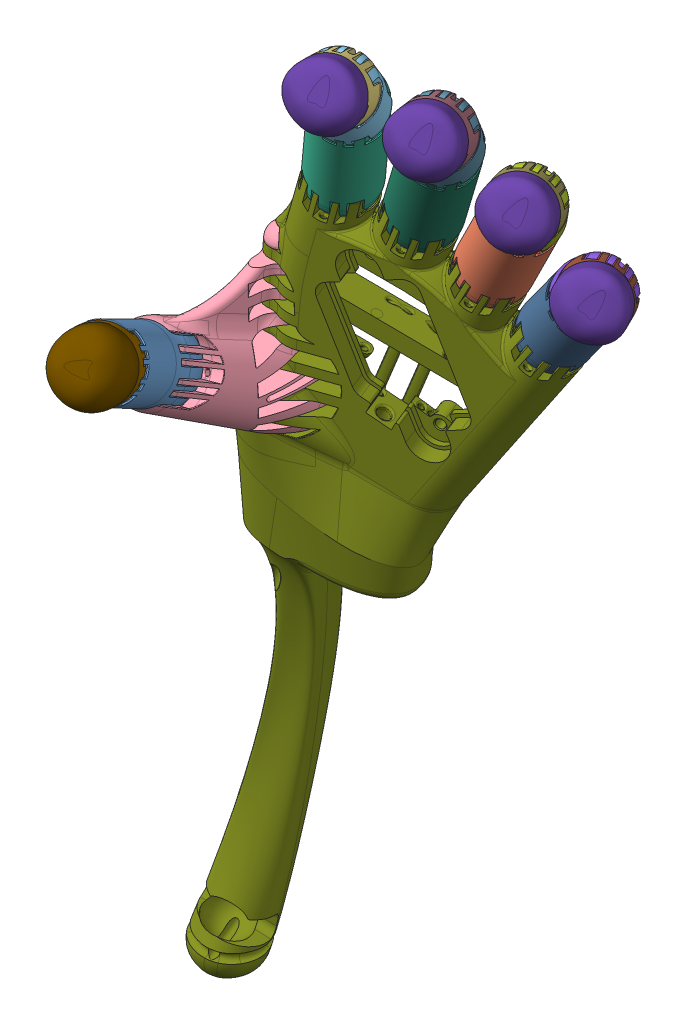
SolidWorks assembly hand_links_0, configuration linksStandard. Lengths in mm.
Overall size (174.74 277.21 120.1).
21 component instances, 18 part files, 45 mates.
Components (placement in the parent):
- p-daumen-seg-2-step-v01-2: p-daumen-seg-2-step-v01 [linksStandard] at (-105.8085 -71.1368 89.6014) x (-0.231233 0.848379 -0.476218) z (0.953119 0.09934 -0.285823) size (20.69 43.22 21.88)
- p-ringfinger-seg-1-step-v02-2: p-ringfinger-seg-1-step-v02 [linksStandard] at (-82.2721 -87.3923 31.2992) x (0.834897 -0.441986 -0.328018) z (0.167049 -0.364366 0.916151) size (19.08 47.31 19.03)
- p-zeigfinger-seg-3-step-v02-2: p-zeigfinger-seg-3-step-v02 [linksStandard] at (-122.5785 -47.8794 -30.4367) x (0.907236 -0.246273 -0.340988) z (-0.050565 -0.868652 0.492835) size (19.01 23.27 19)
- p-daumen-seg-1-step-v01-2: p-daumen-seg-1-step-v01 [linksStandard] at (-100.474 -88.1528 56.8024) x (-0.144961 -0.741973 0.654571) z (-0.983441 0.035324 -0.177752) size (51 61.46 25.3)
- p-zeigfinger-seg-2-step-v02-2: p-zeigfinger-seg-2-step-v02 [linksStandard] at (-137.8276 -111.3733 -25.0048) x (0.907236 -0.246273 -0.340988) z (0.095303 -0.66924 0.736909) size (19.2 35.59 19.73)
- p-zeigfinger-seg-1-step-v02-2: p-zeigfinger-seg-1-step-v02 [linksStandard] at (-104.3344 -77.6629 39.9073) x (0.907236 -0.246273 -0.340988) z (0.229675 -0.389107 0.892101) size (19.08 48.86 19.03)
- p-ringfinger-seg-2-step-v02-2: p-ringfinger-seg-2-step-v02 [linksStandard] at (-123.5586 -119.2331 -31.035) x (0.834897 -0.441986 -0.328018) z (-0.022395 -0.622741 0.782107) size (19.2 37.93 19.73)
- p-kleinerfinger-seg-2-step-v02-2: p-kleinerfinger-seg-2-step-v02 [linksStandard] at (-101.3561 -110.3796 -16.5005) x (0.780209 -0.540448 -0.314944) z (-0.081347 -0.586882 0.805575) size (19.09 34.83 19.68)
- p-daumen-seg-3-v01-2: p-daumen-seg-3-v01 [linksStandard] at (-101.2428 -59.0462 109.0287) x (0.509394 0.522602 0.68367) z (0.828884 -0.084496 -0.553002) size (28.23 20.09 20.4)
- p-kleinerfinger-seg-1-step-v02-2: p-kleinerfinger-seg-1-step-v02 [linksStandard] at (-75.3128 -98.5287 27.5212) x (0.780209 -0.540448 -0.314944) z (0.135682 -0.345286 0.928638) size (19.08 41.2 19.03)
- p-kleinerfinger-seg-3-step-v02-2: p-kleinerfinger-seg-3-step-v02 [linksStandard] at (-96.9388 -81.2121 -55.4508) x (0.780209 -0.540448 -0.314944) z (-0.288564 -0.757692 0.585349) size (18.67 21.72 17.82)
- p-ringfinger-seg-3-step-v02-2: p-ringfinger-seg-3-step-v02 [linksStandard] at (-96.3832 -59.946 -41.5997) x (0.834897 -0.441986 -0.328018) z (-0.209139 -0.806005 0.55373) size (19.01 23.27 19)
- p-mittelfinger-seg-3-step-v02-2: p-mittelfinger-seg-3-step-v02 [linksStandard] at (-88.7612 -32.6771 -4.2991) x (0.875864 -0.346025 -0.336346) z (-0.131494 -0.84177 0.523577) size (19.01 24.05 19)
- p-mittelfinger-seg-2-step-v02-2: p-mittelfinger-seg-2-step-v02 [linksStandard] at (-85.001 -49.817 23.2747) x (0.875864 -0.346025 -0.336346) z (0.035235 -0.649287 0.759727) size (19.2 39.53 19.78)
- p-mittelfinger-seg-1-step-v02-2: p-mittelfinger-seg-1-step-v02 [linksStandard] at (-109.2309 -113.1606 25.1963) x (0.875864 -0.346025 -0.336346) z (0.197714 -0.378491 0.904242) size (19.08 48.86 19.03)
- p-handfläche-teil-2-v01-2: p-handfläche-teil-2-v01 [linksStandard] at (-93.4775 -100.6279 53.4744) x (-0.875864 0.346025 0.336346) z (-0.336346 0.062043 -0.939693) size (71.41 221.99 39.87)
- p-fingerkuppe-12.4-1: p-fingerkuppe-12.4 [linksStandard] at (-9.4631 -23.5529 62.3085) x (0.780209 -0.540448 -0.314944) z (-0.288564 -0.757692 0.585349) size (17.55 9.03 17.93)
- p-fingerkuppe-12.4-5: p-fingerkuppe-12.4 [linksStandard] at (-19.9026 -0.8036 73.3735) x (0.834897 -0.441986 -0.328018) z (-0.209139 -0.806005 0.55373) size (17.55 9.03 17.93)
- p-fingerkuppe-12.4-6: p-fingerkuppe-12.4 [linksStandard] at (-37.0914 13.4349 82.8131) x (0.875864 -0.346025 -0.336346) z (-0.131494 -0.84177 0.523577) size (17.55 9.03 17.93)
- p-fingerkuppe-12.4-7: p-fingerkuppe-12.4 [linksStandard] at (-60.7662 15.7541 88.0632) x (0.907236 -0.246273 -0.340988) z (-0.050565 -0.868652 0.492835) size (17.55 9.03 17.93)
- p-fingerkuppe-18-1: p-fingerkuppe-18 [Standard] at (-90.1493 -47.6651 123.9175) x (0.231233 -0.848379 0.476218) z (-0.828884 0.084496 0.553002) size (18.01 12.53 19.06)
Mates (geometry in assembly coordinates):
- Concentric1: concentric aligned: cylinder of p-daumen-seg-1-step-v01-2 through (-99.5527 -52.2226 58.8448) axis (-0.025594 -0.998061 -0.056736) radius 1; cylinder of p-handfläche-teil-2-v01-2 through (-99.5527 -52.2226 58.8448) axis (-0.025594 -0.998061 -0.056736) radius 1.3
- Coincident1: coincident anti-aligned: plane of p-daumen-seg-1-step-v01-2 through (-99.5527 -52.2226 58.8448) normal (-0.025594 -0.998061 -0.056736); plane of p-handfläche-teil-2-v01-2 through (-88.5057 -53.1849 70.7899) normal (0.025594 0.998061 0.056736)
- Concentric2: concentric anti-aligned: cylinder of p-daumen-seg-2-step-v01-2 through (-107.6815 -64.2649 85.7441) axis (0.231233 -0.848379 0.476218) radius 3.3; cylinder of p-daumen-seg-1-step-v01-2 through (-107.7393 -64.0528 85.625) axis (-0.231233 0.848379 -0.476218) radius 3.6
- Distance1: distance = 0.25 mm anti-aligned: plane of p-daumen-seg-2-step-v01-2 through (-119.5206 -72.725 78.311) normal (-0.231233 0.848379 -0.476218); plane of p-daumen-seg-1-step-v01-2 through (-96.3972 -65.2495 79.8758) normal (0.231233 -0.848379 0.476218)
- Concentric3: concentric aligned: cylinder of p-daumen-seg-2-step-v01-2 through (-102.9886 -52.641 105.4333) axis (0.231233 -0.848379 0.476218) radius 3; cylinder of p-daumen-seg-3-v01-2 through (-102.9076 -52.9379 105.5999) axis (0.231233 -0.848379 0.476218) radius 3.3
- Distance2: distance = 0.25 mm anti-aligned: plane of p-daumen-seg-3-v01-2 through (-103.6879 -54.4436 120.9353) normal (0.231233 -0.848379 0.476218); plane of p-daumen-seg-2-step-v01-2 through (-112.2538 -66.1057 104.8438) normal (-0.231233 0.848379 -0.476218)
- Concentric4: concentric aligned: cylinder of p-zeigfinger-seg-1-step-v02-2 through (-78.2575 -33.4931 52.4593) axis (-0.907236 0.246273 0.340988) radius 3.05; cylinder of p-handfläche-teil-2-v01-2 through (-91.8207 -29.8113 57.557) axis (-0.907236 0.246273 0.340988) radius 3.35
- Concentric5: concentric aligned: cylinder of p-zeigfinger-seg-2-step-v02-2 through (-67.2492 -5.8892 61.6651) axis (-0.907236 0.246273 0.340988) radius 3.05; cylinder of p-zeigfinger-seg-1-step-v02-2 through (-69.109 -5.3843 62.3641) axis (-0.907236 0.246273 0.340988) radius 3.35
- Concentric6: concentric aligned: cylinder of p-zeigfinger-seg-3-step-v02-2 through (-59.875 6.6394 72.0896) axis (-0.907236 0.246273 0.340988) radius 3.05; cylinder of p-zeigfinger-seg-2-step-v02-2 through (-61.7349 7.1443 72.7886) axis (-0.907236 0.246273 0.340988) radius 3.35
- Distance3: distance = 0.25 mm anti-aligned: plane of p-zeigfinger-seg-3-step-v02-2 through (-69.5267 12.1422 63.5511) normal (0.907236 -0.246273 -0.340988); plane of p-zeigfinger-seg-2-step-v02-2 through (-63.5081 19.9985 73.157) normal (-0.907236 0.246273 0.340988)
- Distance4: distance = 0.25 mm anti-aligned: plane of p-zeigfinger-seg-1-step-v02-2 through (-72.5115 6.6749 58.9719) normal (-0.907236 0.246273 0.340988); plane of p-zeigfinger-seg-2-step-v02-2 through (-78.0737 -4.3864 52.8951) normal (0.907236 -0.246273 -0.340988)
- Distance5: distance = 0.25 mm anti-aligned: plane of p-zeigfinger-seg-1-step-v02-2 through (-85.9997 -19.9607 50.8268) normal (-0.907236 0.246273 0.340988); plane of p-handfläche-teil-2-v01-2 through (-82.3694 -23.3241 63.6479) normal (0.907236 -0.246273 -0.340988)
- Concentric7: concentric aligned: cylinder of p-mittelfinger-seg-1-step-v02-2 through (-61.7671 -38.0544 46.2557) axis (-0.875864 0.346025 0.336346) radius 3.05; cylinder of p-handfläche-teil-2-v01-2 through (-74.9489 -32.8468 51.3177) axis (-0.875864 0.346025 0.336346) radius 3.35
- Concentric8: concentric aligned: cylinder of p-mittelfinger-seg-2-step-v02-2 through (-48.116 -11.3285 54.4576) axis (-0.875864 0.346025 0.336346) radius 3.05; cylinder of p-mittelfinger-seg-1-step-v02-2 through (-49.8239 -10.6537 55.1134) axis (-0.875864 0.346025 0.336346) radius 3.35
- Concentric9: concentric aligned: cylinder of p-mittelfinger-seg-3-step-v02-2 through (-37.5912 3.4037 66.56) axis (-0.875864 0.346025 0.336346) radius 3.05; cylinder of p-mittelfinger-seg-2-step-v02-2 through (-39.3867 4.113 67.2495) axis (-0.875864 0.346025 0.336346) radius 3.35
- Distance6: distance = 0.25 mm anti-aligned: plane of p-mittelfinger-seg-3-step-v02-2 through (-46.7262 9.5281 57.8777) normal (0.875864 -0.346025 -0.336346); plane of p-mittelfinger-seg-2-step-v02-2 through (-39.8872 17.0843 67.1701) normal (-0.875864 0.346025 0.336346)
- Distance8: distance = 0.25 mm anti-aligned: plane of p-mittelfinger-seg-1-step-v02-2 through (-73.4956 -39.6431 38.755) normal (0.875864 -0.346025 -0.336346); plane of p-handfläche-teil-2-v01-2 through (-75.3762 -64.2621 58.4419) normal (-0.875864 0.346025 0.336346)
- Distance9: distance = 0.25 mm anti-aligned: plane of p-mittelfinger-seg-2-step-v02-2 through (-52.7638 3.5415 56.1932) normal (-0.875864 0.346025 0.336346); plane of p-mittelfinger-seg-1-step-v02-2 through (-62.4727 -12.1885 47.8366) normal (0.875864 -0.346025 -0.336346)
- Concentric10: concentric aligned: cylinder of p-ringfinger-seg-1-step-v02-2 through (-47.7431 -48.2734 40.5613) axis (-0.834897 0.441986 0.328018) radius 3.05; cylinder of p-handfläche-teil-2-v01-2 through (-60.2248 -41.6658 45.4652) axis (-0.834897 0.441986 0.328018) radius 3.35
- Concentric11: concentric aligned: cylinder of p-ringfinger-seg-1-step-v02-2 through (-33.9127 -23.1632 48.0262) axis (-0.834897 0.441986 0.328018) radius 3.35; cylinder of p-ringfinger-seg-2-step-v02-2 through (-32.2011 -24.0693 47.3538) axis (-0.834897 0.441986 0.328018) radius 3.05
- Concentric12: concentric aligned: cylinder of p-ringfinger-seg-2-step-v02-2 through (-22.7497 -10.1292 58.724) axis (-0.834897 0.441986 0.328018) radius 3.35; cylinder of p-ringfinger-seg-3-step-v02-2 through (-21.1217 -10.991 58.0844) axis (-0.834897 0.441986 0.328018) radius 3.05
- Distance10: distance = 0.25 mm anti-aligned: plane of p-ringfinger-seg-3-step-v02-2 through (-23.0457 3.6561 63.3275) normal (-0.834897 0.441986 0.328018); plane of p-ringfinger-seg-2-step-v02-2 through (-34.1616 -6.9373 50.0706) normal (0.834897 -0.441986 -0.328018)
- Distance11: distance = 0.25 mm anti-aligned: plane of p-ringfinger-seg-1-step-v02-2 through (-34.9658 -10.933 43.8044) normal (-0.834897 0.441986 0.328018); plane of p-ringfinger-seg-2-step-v02-2 through (-42.6966 -21.0815 38.5641) normal (0.834897 -0.441986 -0.328018)
- Distance12: distance = 0.25 mm anti-aligned: plane of p-ringfinger-seg-1-step-v02-2 through (-52.7299 -33.6316 38.0159) normal (-0.834897 0.441986 0.328018); plane of p-handfläche-teil-2-v01-2 through (-49.5716 -36.7524 51.022) normal (0.834897 -0.441986 -0.328018)
- Concentric13: concentric aligned: cylinder of p-kleinerfinger-seg-1-step-v02-2 through (-35.8151 -61.8258 35.3971) axis (-0.780209 0.540448 0.314944) radius 3.05; cylinder of p-handfläche-teil-2-v01-2 through (-47.4792 -53.7461 40.1055) axis (-0.780209 0.540448 0.314944) radius 3.35
- Distance13: distance = 0.25 mm anti-aligned: plane of p-kleinerfinger-seg-1-step-v02-2 through (-39.2409 -46.8425 32.3155) normal (-0.780209 0.540448 0.314944); plane of p-handfläche-teil-2-v01-2 through (-36.3144 -49.7894 45.416) normal (0.780209 -0.540448 -0.314944)
- Concentric14: concentric aligned: cylinder of p-kleinerfinger-seg-2-step-v02-2 through (-21.6062 -43.8959 39.9877) axis (-0.780209 0.540448 0.314944) radius 3.05; cylinder of p-kleinerfinger-seg-1-step-v02-2 through (-23.1276 -42.842 40.6019) axis (-0.780209 0.540448 0.314944) radius 3.35
- Distance14: distance = 0.25 mm anti-aligned: plane of p-kleinerfinger-seg-2-step-v02-2 through (-16.9349 -32.8305 37.9694) normal (-0.780209 0.540448 0.314944); plane of p-kleinerfinger-seg-1-step-v02-2 through (-29.6544 -46.659 30.9831) normal (0.780209 -0.540448 -0.314944)
- Concentric15: concentric aligned: cylinder of p-kleinerfinger-seg-2-step-v02-2 through (-12.5542 -32.4988 49.2049) axis (-0.780209 0.540448 0.314944) radius 3.35; cylinder of p-kleinerfinger-seg-3-step-v02-2 through (-11.0327 -33.5527 48.5908) axis (-0.780209 0.540448 0.314944) radius 3.05
- Distance15: distance = 0.25 mm anti-aligned: plane of p-kleinerfinger-seg-3-step-v02-2 through (-5.0225 -22.9744 50.7253) normal (-0.780209 0.540448 0.314944); plane of p-kleinerfinger-seg-2-step-v02-2 through (-17.1689 -32.6684 38.0639) normal (0.780209 -0.540448 -0.314944)
- Concentric16: concentric anti-aligned: cylinder of p-kleinerfinger-seg-3-step-v02-2 through (-130.2377 -103.1608 -100.2775) axis (-0.554981 -0.365813 -0.747112) radius 2; cylinder of p-fingerkuppe-12.4-1 through (-42.762 -45.5017 17.4817) axis (0.554981 0.365813 0.747112) radius 2
- Coincident20: coincident anti-aligned: plane of p-kleinerfinger-seg-3-step-v02-2 through (-8.7287 -29.6499 52.7018) normal (0.554981 0.365813 0.747112); plane of p-fingerkuppe-12.4-1 through (-8.7287 -29.6499 52.7018) normal (-0.554981 -0.365813 -0.747112)
- Concentric17: concentric anti-aligned: cylinder of p-ringfinger-seg-3-step-v02-2 through (-126.9307 -83.5684 -87.5218) axis (-0.509125 -0.393706 -0.765367) radius 2; cylinder of p-fingerkuppe-12.4-5 through (-50.4501 -24.426 27.4515) axis (0.509125 0.393706 0.765367) radius 2
- Coincident21: coincident anti-aligned: plane of p-ringfinger-seg-3-step-v02-2 through (-18.475 -6.4141 63.5509) normal (0.509125 0.393706 0.765367); plane of p-fingerkuppe-12.4-5 through (-18.475 -6.4141 63.5509) normal (-0.509125 -0.393706 -0.765367)
- Coincident22: coincident anti-aligned: plane of p-ringfinger-seg-3-step-v02-2 through (-17.864 -5.9417 64.4693) normal (-0.060984 -0.87051 0.488358); plane of p-fingerkuppe-12.4-5 through (-17.864 -5.9417 64.4693) normal (0.060984 0.87051 -0.488358)
- Coincident23: coincident anti-aligned: plane of p-kleinerfinger-seg-3-step-v02-2 through (-8.0627 -29.2109 53.5984) normal (-0.148698 -0.840029 0.521767); plane of p-fingerkuppe-12.4-1 through (-8.0627 -29.2109 53.5984) normal (0.148698 0.840029 -0.521767)
- Concentric18: concentric anti-aligned: cylinder of p-mittelfinger-seg-3-step-v02-2 through (-116.619 -57.5384 -51.2657) axis (-0.464297 -0.414355 -0.782776) radius 2; cylinder of p-fingerkuppe-12.4-6 through (-64.9492 -11.4264 35.8465) axis (0.464297 0.414355 0.782776) radius 2
- Coincident24: coincident anti-aligned: plane of p-mittelfinger-seg-3-step-v02-2 through (-35.0723 8.3436 72.813) normal (0.464297 0.414355 0.782776); plane of p-fingerkuppe-12.4-6 through (-35.0723 8.3436 72.813) normal (-0.464297 -0.414355 -0.782776)
- Coincident25: coincident anti-aligned: plane of p-mittelfinger-seg-3-step-v02-2 through (-34.5152 8.8408 73.7524) normal (0.022596 -0.889068 0.457217); plane of p-fingerkuppe-12.4-6 through (-34.5152 8.8408 73.7524) normal (-0.022596 0.889068 -0.457217)
- Concentric19: concentric anti-aligned: cylinder of p-zeigfinger-seg-3-step-v02-2 through (-147.6328 -73.672 -78.4682) axis (-0.417572 -0.429876 -0.800525) radius 2; cylinder of p-fingerkuppe-12.4-7 through (-85.8205 -10.0385 40.0317) axis (0.417572 0.429876 0.800525) radius 2
- Coincident26: coincident anti-aligned: plane of p-zeigfinger-seg-3-step-v02-2 through (-58.2087 11.2433 77.9088) normal (0.417572 0.429876 0.800525); plane of p-fingerkuppe-12.4-7 through (-58.2087 11.2433 77.9088) normal (-0.417572 -0.429876 -0.800525)
- Coincident27: coincident anti-aligned: plane of p-zeigfinger-seg-3-step-v02-2 through (-57.7076 11.7592 78.8694) normal (0.107743 -0.89822 0.426136); plane of p-fingerkuppe-12.4-7 through (-57.7076 11.7592 78.8694) normal (-0.107743 0.89822 -0.426136)
- Concentric20: concentric aligned: cylinder of p-daumen-seg-3-v01-2 through (-131.8064 -90.4024 68.0085) axis (0.509394 0.522602 0.68367) radius 2.5; cylinder of p-fingerkuppe-18-1 through (-120.7129 -79.0213 82.8973) axis (0.509394 0.522602 0.68367) radius 2.5
- Coincident28: coincident anti-aligned: plane of p-daumen-seg-3-v01-2 through (-95.7627 -61.585 120.4568) normal (0.856445 -0.230532 -0.461906); plane of p-fingerkuppe-18-1 through (-95.1242 -59.5699 120.6347) normal (-0.856445 0.230532 0.461906)
- Coincident29: coincident anti-aligned: plane of p-daumen-seg-3-v01-2 through (-95.7627 -61.585 120.4568) normal (0.509394 0.522602 0.68367); plane of p-fingerkuppe-18-1 through (-95.8883 -60.3538 119.6092) normal (-0.509394 -0.522602 -0.68367)
